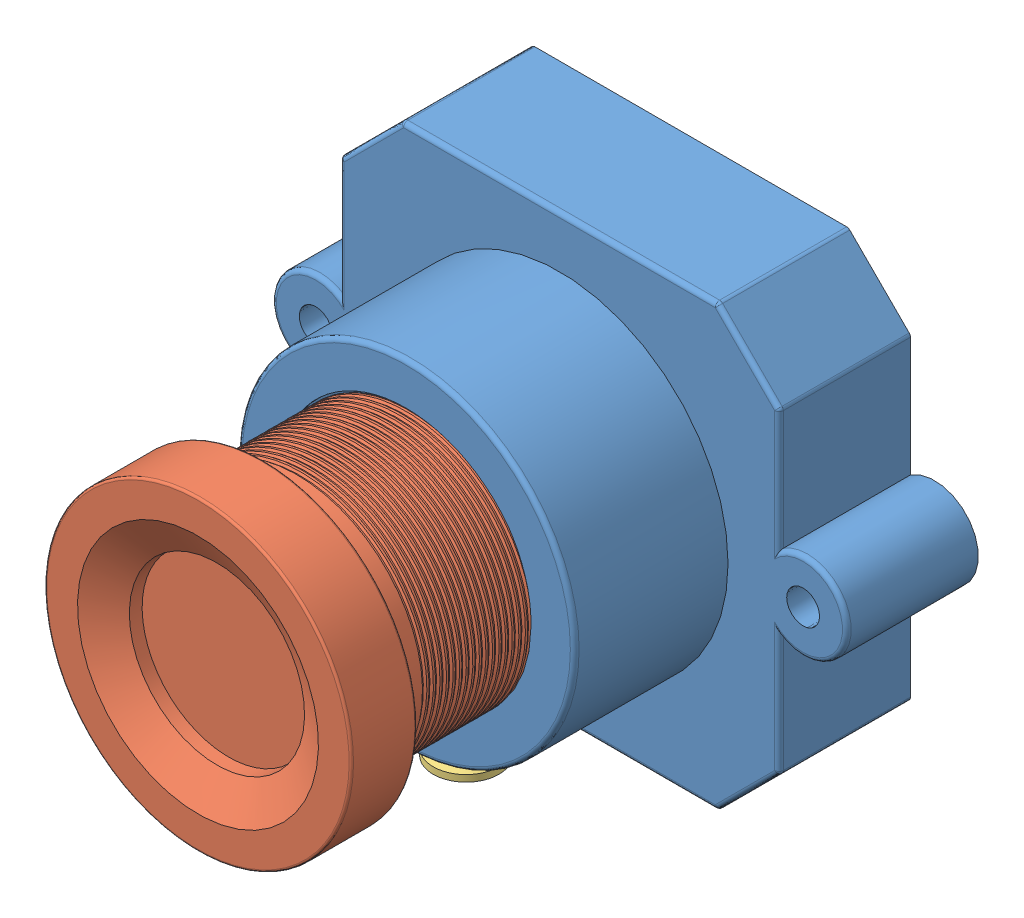
SolidWorks assembly 摄像头-1, configuration 默认. Lengths in mm.
Overall size (26.25 20.05 22.5).
3 component instances, 3 part files, 3 mates.
Components (placement in the parent):
- 底座-1: 底座 [默认] at (-3.1409 0.8701 20.4725) size (26.25 20.05 13.15)
- 镜头-1: 镜头 [默认] at (-3.1409 0.8701 39.9725) x (0.192959 -0.981207 0) z (0 0 -1) size (14 14 15.3)
- 螺钉-1: 螺钉 [ISO 7047 - M1.6 x 3 - Z --- 3N] at (-3.1295 -8.8207 30.7429) x (-0.001176 0.999999 0) z (-0.196345 -0.000231 0.980535) size (3.37 3 3)
Mates (geometry in assembly coordinates):
- 同心1: concentric aligned: circle of 底座-1; circle of 镜头-1
- 距离1: distance = 2.5 mm aligned: plane of 镜头-1 through (-3.1409 0.8701 27.9725) normal (0 0 -1); plane of 底座-1 through (-3.1409 0.8701 25.4725) normal (0 0 -1)
- 同心5: concentric anti-aligned: cylinder of 底座-1 through (-3.1342 -4.8299 30.7429) axis (-0.001176 0.999999 0) radius 0.75; circle of 螺钉-1
